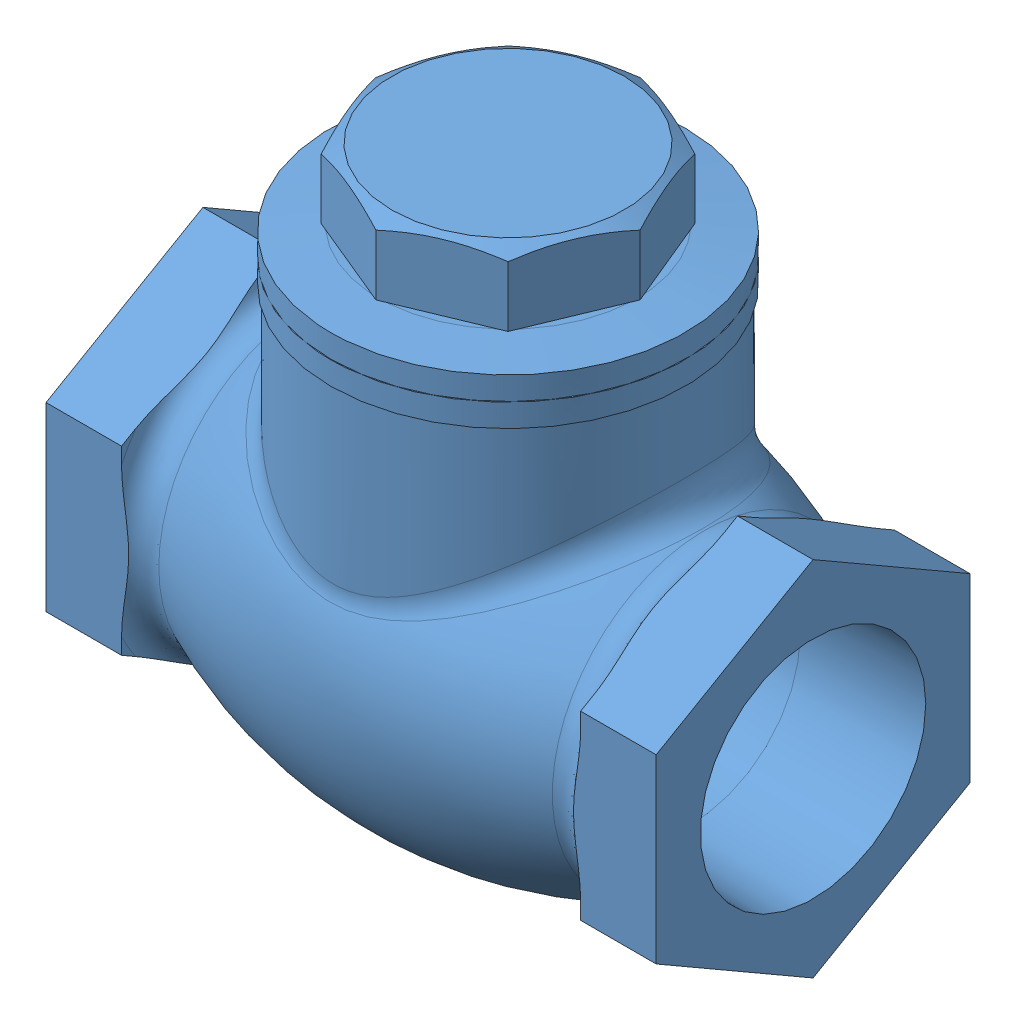
SolidWorks assembly waste valve, configuration Default. Lengths in mm.
Overall size (68.72 65.77 46.04).
2 component instances, 2 part files, 5 mates.
Components (placement in the parent):
- Brass swing check valve.STEP_1-1: Brass swing check valve.STEP_1 [Default] at origin size (68.72 65.77 46.04)
- inner stopper of waste valve custom nv-1: inner stopper of waste valve custom nv [Default] at (0.2919 5.3572 -0.0917) x (0 -0.978833 0.204659) z (0 0.204659 0.978833) size (18 30 18)
Mates (geometry in assembly coordinates):
- Concentric1: concentric aligned: cylinder of Brass swing check valve.STEP_1-1 through (0.6094 5.3572 -0.0917) axis (1 0 0) radius 1.3048; cylinder of inner stopper of waste valve custom nv-1 through (-26.7081 5.3572 -0.0917) axis (1 0 0) radius 1.305
- LimitDistance1: limit distance = 24 mm anti-aligned: plane of inner stopper of waste valve custom nv-1 through (-24.7081 4.0798 0.1753) normal (1 0 0); plane of Brass swing check valve.STEP_1-1 through (-0.7081 5.3572 -0.0917) normal (-1 0 0)
- Coincident1: coincident aligned: plane of Brass swing check valve.STEP_1-1 through (0 0 0) normal (0 0 1)
- Coincident2: coincident aligned: plane of Brass swing check valve.STEP_1-1 through (0 0 0) normal (0 1 0)
- Coincident3: coincident aligned: plane of Brass swing check valve.STEP_1-1 through (0 0 0) normal (1 0 0)
